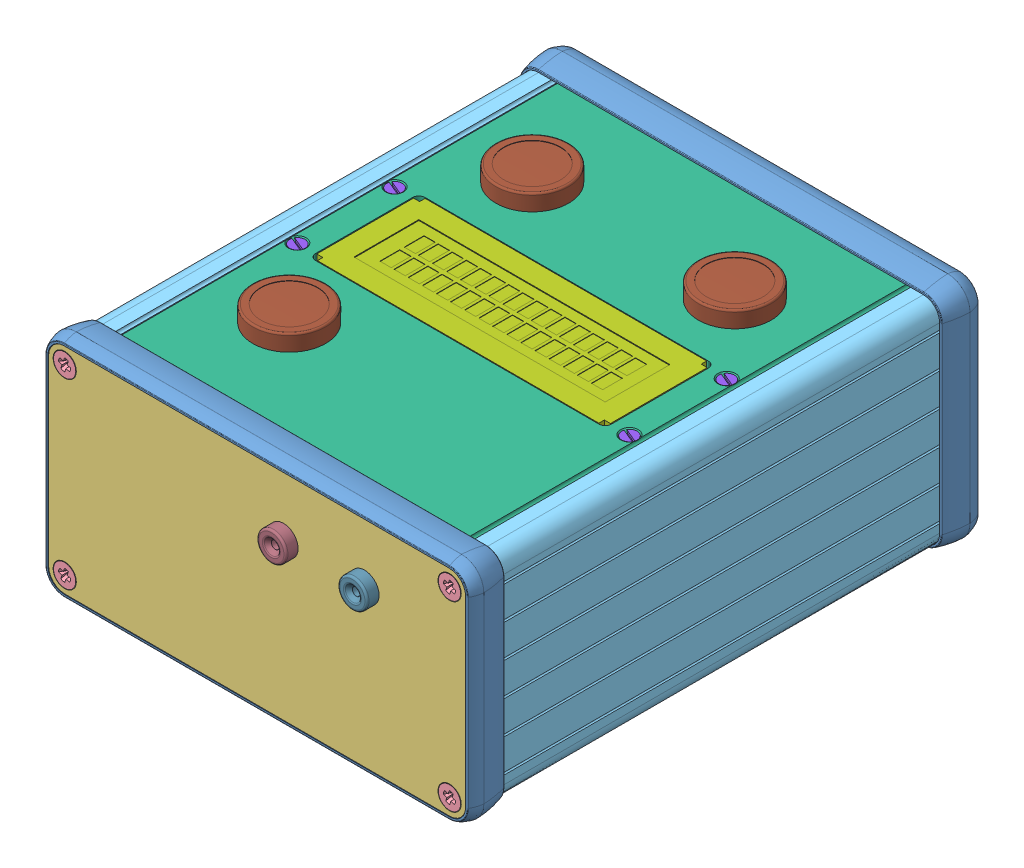
SolidWorks assembly Open_tES_Stimulator, configuration Défaut. Lengths in mm.
Overall size (106.15 58.4 134.65).
41 component instances, 17 part files, 26 mates.
Components (placement in the parent):
- Enclosure-1: Enclosure [Défaut] at (-9.6601 70.4215 -26.5) size (106.15 56.13 126.01)
  - Bezel Open-1: Bezel Open [Défaut] at (-29.0593 12.0561 -60) x (1 0 0) z (0 0 -1) size (106.13 56.13 9.01)
  - Bezel Open-2: Bezel Open [Défaut] at (-29.0793 -12.5761 60) size (106.13 56.13 9.01)
  - Back End Plate-5: Back End Plate [Défaut] at (0.01 -0.26 -62.15) x (1 0 0) z (0 0 -1) size (103 53 1.5)
  - Front End Plate-4: Front End Plate [Défaut] at (-0.01 -0.26 62.15) size (103 53 1.5)
  - 1455 screw-4-2: 1455 screw-4 [Défaut] at (-47.5 22.24 -62.9254) x (0.43184 0.90195 0) z (0 0 1) size (5.5 5.5 8)
  - 1455 screw-4-4: 1455 screw-4 [Défaut] at (-47.52 -22.76 62.9254) x (-0.950123 0.311876 0) z (0 0 -1) size (5.5 5.5 8)
  - Back End Plate-6: Back End Plate [Défaut] at (0.01 -0.26 -62.15) x (1 0 0) z (0 0 -1) size (103 53 1.5)
  - 1455N Extrusion 120mm-4-1: 1455N Extrusion 120mm-4 [Défaut] x (1 0 0) z (0 0 -1) size (103 53 120)
  - Cover-1: Cover [Défaut] at (0 26.08 0) x (-1 0 0) z (0 0 1) size (91.9 4.32 120)
  - 1455 screw-4-9: 1455 screw-4 [Défaut] at (-47.5 -22.76 -62.9254) x (0.43184 0.90195 0) z (0 0 1) size (5.5 5.5 8)
  - 1455 screw-4-10: 1455 screw-4 [Défaut] at (47.52 22.24 -62.9254) x (0.43184 0.90195 0) z (0 0 1) size (5.5 5.5 8)
  - 1455 screw-4-11: 1455 screw-4 [Défaut] at (47.52 -22.76 -62.9254) x (0.43184 0.90195 0) z (0 0 1) size (5.5 5.5 8)
  - 1455 screw-4-12: 1455 screw-4 [Défaut] at (-47.52 22.24 62.9254) x (-0.950123 0.311876 0) z (0 0 -1) size (5.5 5.5 8)
  - 1455 screw-4-13: 1455 screw-4 [Défaut] at (47.5 -22.76 62.9254) x (-0.950123 0.311876 0) z (0 0 -1) size (5.5 5.5 8)
  - 1455 screw-4-14: 1455 screw-4 [Défaut] at (47.5 22.24 62.9254) x (-0.950123 0.311876 0) z (0 0 -1) size (5.5 5.5 8)
- LCD Display 16x2-6: LCD Display 16x2 [Défaut] at (-9.6601 92.0015 -26.5) x (1 0 0) z (0 0 -1) size (85 6.1 30)
- Screw_FS_M2-16-1: Screw_FS_M2-16 [Défaut] at (-50.6601 96.3215 -38.5) x (0 -1 0) z (0.390234 0 -0.920716) size (16 3.77 3.8)
- WasherM2-1: WasherM2 [Défaut] at (-50.6601 89.9015 -38.5) x (0 1 0) z (0 0 1) size (0.5 5.5 5.5)
- Nut M2-1: Nut M2 [Défaut] at (-50.6601 89.9015 -38.5) x (0 -1 0) z (0 0 1) size (1.6 4.62 4)
- WasherM2-2: WasherM2 [Défaut] at (31.3399 89.9015 -38.5) x (0 1 0) z (0 0 1) size (0.5 5.5 5.5)
- WasherM2-3: WasherM2 [Défaut] at (-50.6601 89.9015 -14.5) x (0 1 0) z (0 0 1) size (0.5 5.5 5.5)
- WasherM2-4: WasherM2 [Défaut] at (31.3399 89.9015 -14.5) x (0 1 0) z (0 0 1) size (0.5 5.5 5.5)
- Nut M2-2: Nut M2 [Défaut] at (31.3399 89.9015 -38.5) x (0 -1 0) z (0 0 1) size (1.6 4.62 4)
- Nut M2-3: Nut M2 [Défaut] at (-50.6601 89.9015 -14.5) x (0 -1 0) z (0 0 1) size (1.6 4.62 4)
- Nut M2-4: Nut M2 [Défaut] at (31.3399 89.9015 -14.5) x (0 -1 0) z (0 0 1) size (1.6 4.62 4)
- Screw_FS_M2-16-2: Screw_FS_M2-16 [Défaut] at (31.3399 96.3215 -38.5) x (0 -1 0) z (0.390234 0 -0.920716) size (16 3.77 3.8)
- Screw_FS_M2-16-3: Screw_FS_M2-16 [Défaut] at (-50.6601 96.3215 -14.5) x (0 -1 0) z (0.390234 0 -0.920716) size (16 3.77 3.8)
- Screw_FS_M2-16-4: Screw_FS_M2-16 [Défaut] at (31.3399 96.3215 -14.5) x (0 -1 0) z (0.390234 0 -0.920716) size (16 3.77 3.8)
- Pushbutton-4: Pushbutton [Défaut] at (-34.6601 100.5015 -56.5) x (0.232087 0 0.972695) z (0 -1 0) size (18 18 12.9)
- Pushbutton-5: Pushbutton [Défaut] at (-34.6594 100.5015 3.4973) x (-0.232087 0 0.972695) z (0 -1 0) size (18 18 12.9)
- Pushbutton-6: Pushbutton [Défaut] at (15.3461 100.5015 -56.4985) x (-0.232087 0 0.972695) z (0 -1 0) size (18 18 12.9)
- Electronic board-5: Electronic board [Défaut] at (-13.9901 52.8115 -37.9) x (0 0 1) z (0 1 0) size (95.8 63 16.3)
- 2mm Pannel-mount Socket Black-3: 2mm Pannel-mount Socket Black [Default] at (-3.1701 82.1615 39.4) x (-0.383049 0.923728 0) z (0 0 1) size (7.21 7.21 24)
- 2mm Pannel-mount Socket Red-3: 2mm Pannel-mount Socket Red [Default] at (16.8299 82.1615 39.4) x (-0.383049 0.923728 0) z (0 0 1) size (7.21 7.21 24)
- switch onoff-1: switch onoff [Default] at (-30.9133 69.9938 -56.8954) x (0 -1 0) z (0 0 -1) size (21.7 15 24.75)
- DC Plug-1: DC Plug [Défaut] at (-17.1501 78.1615 -78.9) x (-0.912489 0.409101 0) z (0 0 -1) size (14 14 17.5)
- Spacer-1: Spacer [Default] at (-50.6601 91.0015 -14.5) x (0 1 0) z (0.984938 0 0.172907) size (2.85 3.2 3.2)
- Spacer-2: Spacer [Default] at (31.3399 95.8515 -14.5) x (0 -1 0) z (-0.984938 0 0.172907) size (2.85 3.2 3.2)
- Spacer-3: Spacer [Default] at (31.3399 95.8515 -38.5) x (0 -1 0) z (-0.984938 0 0.172907) size (2.85 3.2 3.2)
- Spacer-4: Spacer [Default] at (-50.6601 91.0015 -38.5) x (0 1 0) z (0.984938 0 0.172907) size (2.85 3.2 3.2)
Mates (geometry in assembly coordinates):
- Coïncidente36: coincident aligned: plane of Enclosure-1/Cover-1 through (-52.6701 96.5015 -26.5) normal (0 1 0); plane of LCD Display 16x2-6 through (25.0899 96.5015 -39.8) normal (0 1 0)
- Coïncidente37: coincident anti-aligned: plane of Enclosure-1/Cover-1; plane of LCD Display 16x2-6
- Coïncidente38: coincident anti-aligned: plane of Enclosure-1/Cover-1; plane of LCD Display 16x2-6 through (-9.6601 92.0015 -26.5) normal (0 0 -1)
- Coaxiale7: concentric aligned: cylinder of Enclosure-1/Cover-1 through (-50.6601 96.5015 -38.5) axis (0 1 0) radius 1.2; cylinder of Screw_FS_M2-16-1 through (-50.6601 80.3215 -38.5) axis (0 1 0) radius 1
- Coïncidente39: coincident: cone of Enclosure-1/Cover-1 through (-50.6601 96.5015 -38.5) axis (0 -1 0); circle of Screw_FS_M2-16-1
- Coaxiale9: concentric anti-aligned: cylinder of Screw_FS_M2-16-1 through (-50.6601 80.3215 -38.5) axis (0 1 0) radius 1; cylinder of WasherM2-1 through (-50.6601 90.4015 -38.5) axis (0 -1 0) radius 1.1
- Coïncidente40: coincident anti-aligned: plane of LCD Display 16x2-6 through (-9.6601 90.4015 -26.5) normal (0 -1 0); plane of WasherM2-1 through (-53.4101 90.4015 -38.5) normal (0 1 0)
- Coaxiale10: concentric anti-aligned: cylinder of Screw_FS_M2-16-1 through (-50.6601 80.3215 -38.5) axis (0 1 0) radius 1; cylinder of Nut M2-1 through (-50.6601 88.3015 -38.5) axis (0 -1 0) radius 0.7835
- Coïncidente41: coincident anti-aligned: plane of WasherM2-1 through (-51.7601 89.9015 -38.5) normal (0 -1 0); plane of Nut M2-1 through (-49.1601 89.9015 -38.5) normal (0 1 0)
- Coaxiale12: concentric aligned: cylinder of Enclosure-1/Cover-1 through (-34.6601 92.2815 -56.5) axis (0 1 0) radius 6.5; cylinder of Pushbutton-4 through (-34.6601 96.5015 -56.5) axis (0 1 0) radius 9
- Coïncidente42: coincident anti-aligned: plane of Enclosure-1/Cover-1 through (-52.6701 96.5015 -26.5) normal (0 1 0); plane of Pushbutton-4 through (-34.6601 96.5015 -56.5) normal (0 -1 0)
- Parallèle2: parallel anti-aligned: plane of Enclosure-1/1455N Extrusion 120mm-4-1 through (41.8399 82.9615 -26.5) normal (1 0 0); plane of Pushbutton-4 through (-40.5352 88.7015 -63.7798) normal (-1 0 0)
- Coïncidente44: coincident anti-aligned: plane of Enclosure-1/Back End Plate-5 through (-9.6501 70.1615 -87.9) normal (0 0 1); plane of Electronic board-5 through (12.0099 60.6615 -87.9) normal (0 0 -1)
- Coaxiale19: concentric anti-aligned: cylinder of Enclosure-1/Back End Plate-6 through (-17.1501 78.1615 -87.9) axis (0 0 -1) radius 6.5; cylinder of DC Plug-1 through (-17.1501 78.1615 -89.4) axis (0 0 1) radius 6.4
- Coïncidente66: coincident anti-aligned: plane of Enclosure-1/Back End Plate-6 through (-9.6501 70.1615 -89.4) normal (0 0 -1); plane of DC Plug-1 through (-17.1501 78.1615 -89.4) normal (0 0 1)
- Coaxiale21: concentric anti-aligned: cylinder of Screw_FS_M2-16-3 through (-50.6601 80.3215 -14.5) axis (0 1 0) radius 1; cylinder of Spacer-1 through (-50.6601 91.0015 -14.5) axis (0 -1 0) radius 1
- Coïncidente70: coincident anti-aligned: plane of Enclosure-1/Cover-1 through (-9.6601 94.8515 -26.5) normal (0 -1 0); plane of Spacer-1 through (-50.833 94.8515 -13.5151) normal (0 1 0)
- Coincident2: coincident: point of Enclosure-1/Back End Plate-5; plane of Electronic board-5
- Coincident6: coincident: line of Enclosure-1/Back End Plate-5 through (24.5099 60.6615 -89.4) axis (-1 0 0); plane of Electronic board-5 through (-13.9901 60.6615 -37.9) normal (0 1 0)
- Coincident7: coincident anti-aligned: plane of Enclosure-1/Back End Plate-6 through (-9.6501 70.1615 -89.4) normal (0 0 -1); plane of switch onoff-1 through (-35.3501 88.7315 -89.4) normal (0 0 1)
- Coincident13: coincident anti-aligned: plane of Enclosure-1/Back End Plate-6 through (-49.6501 86.2615 -87.9) normal (1 0 0); plane of switch onoff-1 through (-49.6501 86.3549 -89.4658) normal (-1 0 0)
- Coincident15: coincident anti-aligned: plane of Enclosure-1/Back End Plate-6 through (-38.1501 68.5615 -87.9) normal (0 1 0); plane of switch onoff-1 through (-46.6475 68.5615 -81.476) normal (0 -1 0)
- Concentric1: concentric aligned: cylinder of Enclosure-1/Front End Plate-4 through (16.8299 82.1615 34.9) axis (0 0 1) radius 2.9; cylinder of 2mm Pannel-mount Socket Red-3 through (16.8299 82.1615 39.4) axis (0 0 1) radius 2.85
- Coincident16: coincident anti-aligned: circle of Enclosure-1/Front End Plate-4; plane of 2mm Pannel-mount Socket Red-3 through (14.1973 81.0698 36.4) normal (0 0 -1)
- Concentric2: concentric aligned: cylinder of Enclosure-1/Front End Plate-4 through (-3.1701 82.1615 34.9) axis (0 0 1) radius 2.9; cylinder of 2mm Pannel-mount Socket Black-3 through (-3.1701 82.1615 39.4) axis (0 0 1) radius 2.85
- Coincident17: coincident anti-aligned: plane of Enclosure-1/Front End Plate-4 through (-9.6701 70.1615 36.4) normal (0 0 1); plane of 2mm Pannel-mount Socket Black-3 through (-5.8027 81.0698 36.4) normal (0 0 -1)
